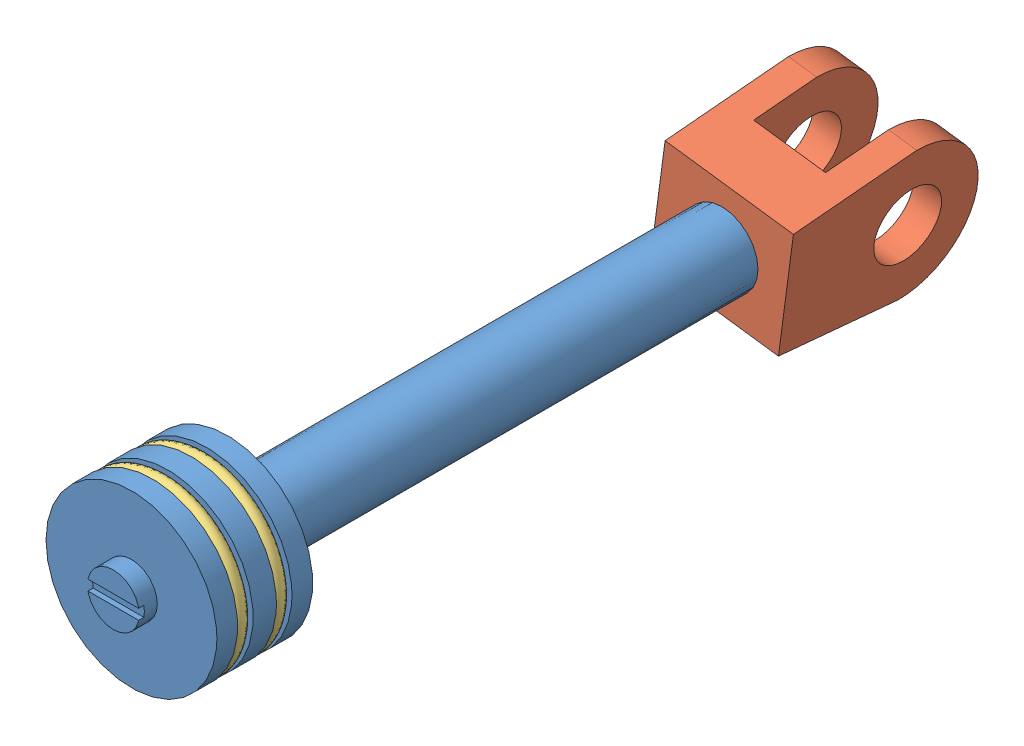
SolidWorks assembly Сборка поршня - МЛИ2.02.00, configuration По умолчанию. Lengths in mm.
Overall size (81.34 81.34 309).
4 component instances, 3 part files, 6 mates.
Components (placement in the parent):
- Поршень - МЛИ2.00.04-1: Поршень - МЛИ2.00.04 [По умолчанию] at origin size (66 66 263)
- Вилка - МЛИ2.00.05-1: Вилка - МЛИ2.00.05 [По умолчанию] at (24.7833 -3.2844 -19) x (0 0 1) z (-0.991332 0.131377 0) size (74 54 50)
- Кольцо уплотнительное-1: Кольцо уплотнительное [По умолчанию] at (0 0 245.1) x (0 0 -1) z (0.983572 -0.180516 0) size (5.8 65.6 65.6)
- Кольцо уплотнительное-2: Кольцо уплотнительное [По умолчанию] at (0 0 230.1) x (0 0 1) z (-0.960016 -0.279944 0) size (5.8 65.6 65.6)
Mates (geometry in assembly coordinates):
- Концентричный1: concentric anti-aligned: cylinder of Поршень - МЛИ2.00.04-1 through (0 0 25) axis (0 0 -1) radius 11; cylinder of Вилка - МЛИ2.00.05-1 through (0 0 5) axis (0 0 1) radius 11
- Совпадение1: coincident anti-aligned: plane of Поршень - МЛИ2.00.04-1 through (0 0 28) normal (0 0 -1); plane of Вилка - МЛИ2.00.05-1 through (-21.893 25.0937 28) normal (0 0 1)
- Совпадение2: coincident anti-aligned: line of Поршень - МЛИ2.00.04-1 through (0 0 216) axis (0 0 -1); line of Кольцо уплотнительное-1 through (0 0 226.5093) axis (0 0 1)
- Касательность2: tangent anti-aligned: plane of Поршень - МЛИ2.00.04-1 through (0 0 248) normal (0 0 -1); torus of Кольцо уплотнительное-1
- Совпадение3: coincident: axis of Кольцо уплотнительное-1 through (0 0 226.5093) axis (0 0 1); axis of Кольцо уплотнительное-2 through (0 0 248.6907) axis (0 0 -1)
- Касательность4: tangent anti-aligned: plane of Поршень - МЛИ2.00.04-1 through (0 0 233) normal (0 0 -1); torus of Кольцо уплотнительное-2
